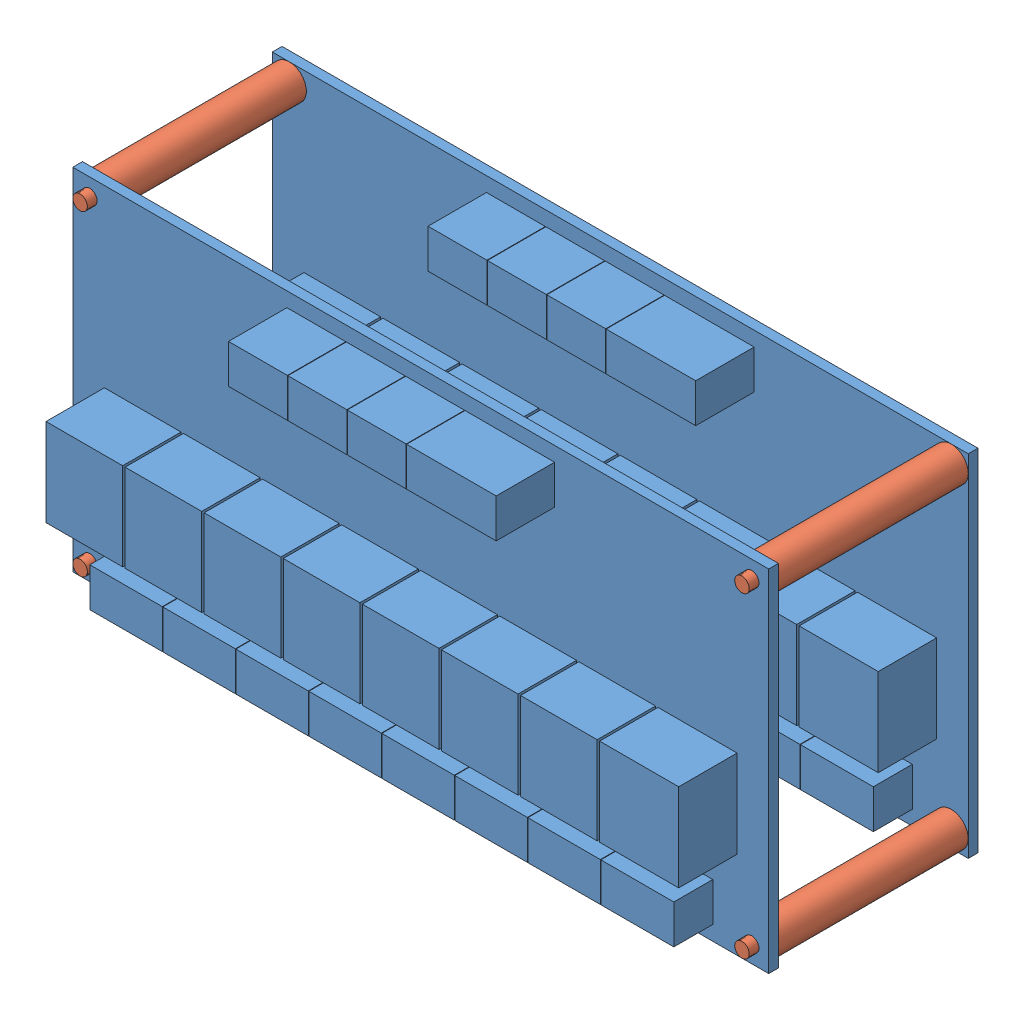
SolidWorks assembly 装配体1, configuration 默认. Lengths in mm.
Overall size (143 72 57).
6 component instances, 2 part files, 11 mates.
Components (placement in the parent):
- 继电器-1: 继电器 [默认] at (-70.4427 -27.2396 136) size (143 72 14)
- 铜柱-1: 铜柱 [默认] at (-66.9427 -23.7396 138) size (7 7 47)
- 铜柱-2: 铜柱 [默认] at (69.0573 41.2604 138) size (7 7 47)
- 铜柱-3: 铜柱 [默认] at (-66.9427 41.2604 138) size (7 7 47)
- 铜柱-4: 铜柱 [默认] at (69.0573 -23.7396 138) size (7 7 47)
- 继电器-2: 继电器 [默认] at (-70.4427 -27.2396 177) size (143 72 14)
Mates (geometry in assembly coordinates):
- 重合1: coincident: plane of 继电器-1 through (-70.4427 -27.2396 138) normal (0 0 1); plane of 铜柱-3 through (-66.9427 41.2604 138) normal (0 0 -1)
- 同心1: concentric anti-aligned: circle of 继电器-1; circle of 铜柱-3
- 重合2: coincident anti-aligned: plane of 继电器-1 through (-70.4427 -27.2396 138) normal (0 0 1); plane of 铜柱-1 through (-66.9427 -23.7396 138) normal (0 0 -1)
- 同心2: concentric anti-aligned: circle of 继电器-1; circle of 铜柱-1
- 重合3: coincident anti-aligned: plane of 继电器-1 through (-70.4427 -27.2396 138) normal (0 0 1); plane of 铜柱-2 through (69.0573 41.2604 138) normal (0 0 -1)
- 同心3: concentric anti-aligned: circle of 继电器-1; circle of 铜柱-2
- 重合4: coincident: plane of 继电器-1 through (-70.4427 -27.2396 138) normal (0 0 1); plane of 铜柱-4 through (69.0573 -23.7396 138) normal (0 0 -1)
- 同心4: concentric anti-aligned: circle of 继电器-1; circle of 铜柱-4
- 重合5: coincident anti-aligned: plane of 铜柱-1 through (-66.9427 -23.7396 177) normal (0 0 1); plane of 继电器-2 through (-70.4427 -27.2396 177) normal (0 0 -1)
- 同心5: concentric anti-aligned: circle of 铜柱-1; circle of 继电器-2
- 同心6: concentric anti-aligned: circle of 铜柱-2; circle of 继电器-2
